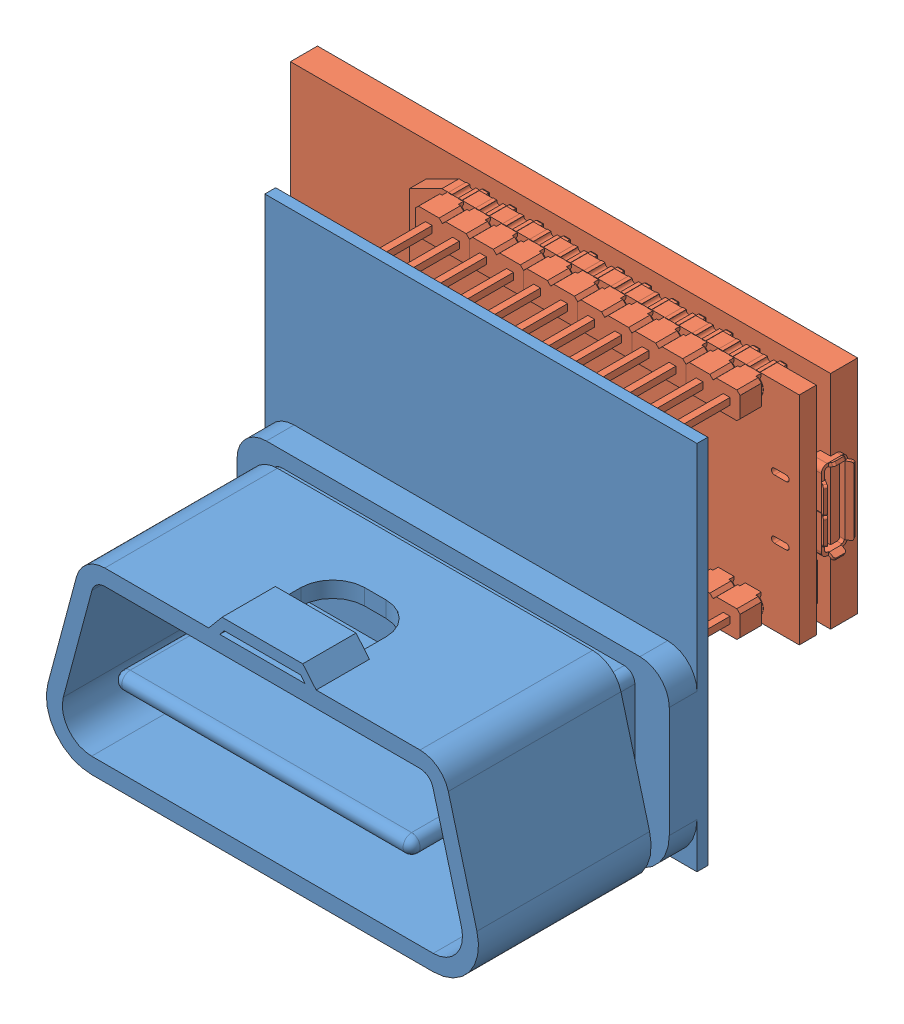
SolidWorks assembly Carloop_Mockup, configuration Default. Lengths in mm.
Overall size (51.72 34.81 36.26).
2 component instances, 2 part files, 2 mates.
Components (placement in the parent):
- COMTECH_OBD-II-16M-E-N-12V_RA-1: COMTECH_OBD-II-16M-E-N-12V_RA [Default] at (32.2972 -1.5223 -24.5931) size (40.55 34.81 21.52)
- particle_photon-1: particle_photon [Default] at (15.2787 61.8079 -16.5117) x (0 1 0) z (-1 0 0) size (20.78 14.74 51.72)
Mates (geometry in assembly coordinates):
- Coincident1: coincident anti-aligned: plane of COMTECH_OBD-II-16M-E-N-12V_RA-1 through (32.2972 -1.5223 -25.6091) normal (0 0 -1); plane of particle_photon-1 through (47.2192 3.6412 -25.6091) normal (0 0 1)
- Parallel1: parallel anti-aligned: line of COMTECH_OBD-II-16M-E-N-12V_RA-1 through (12.0222 24.5827 -25.6091) axis (1 0 0); line of particle_photon-1 through (51.8547 23.0087 -36.5093) axis (-1 0 0)
